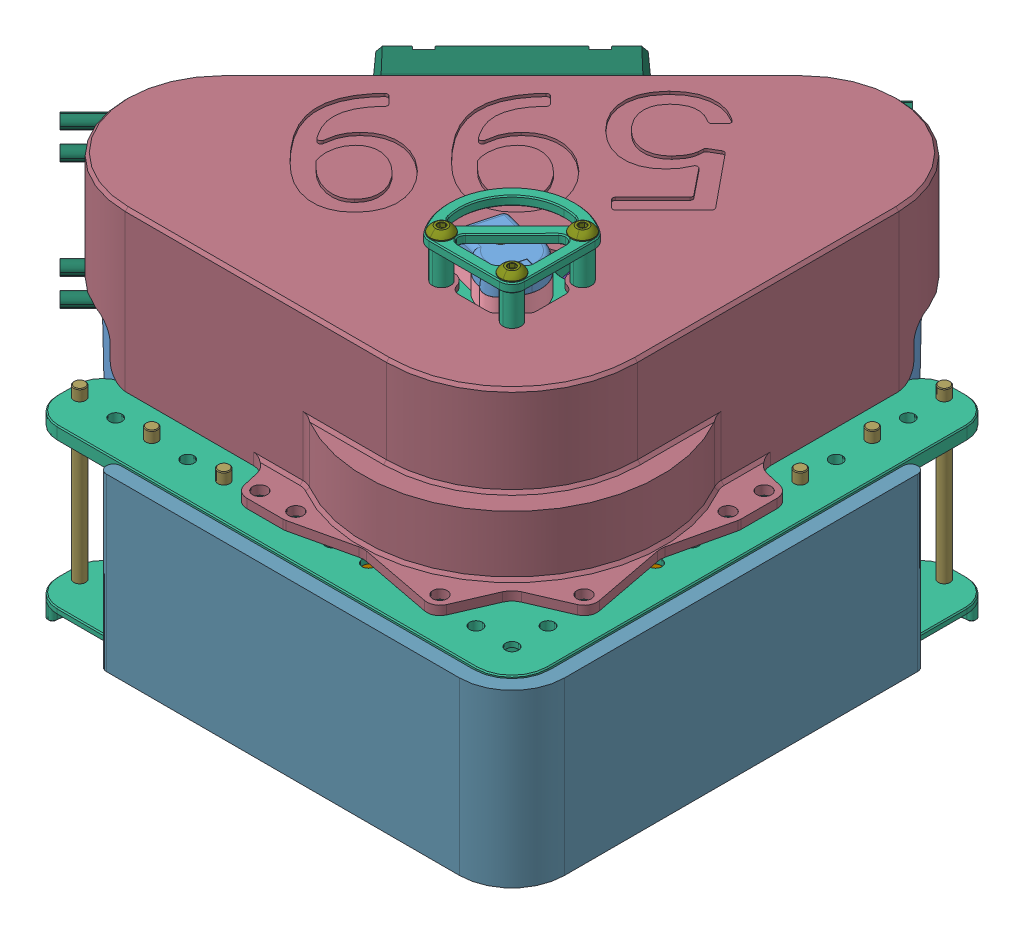
SolidWorks assembly SDS MK4i Swerve Module, NEOs, Deprecated, configuration Default. Lengths in mm.
Overall size (244.9 191.97 235.96).
101 component instances, 51 part files, 24 mates.
Components (placement in the parent):
- SDS MK4i Swerve Module, NEOs(3)^SDS MK4i Swerve Module, NEOs, Deprecated-1: SDS MK4i Swerve Module, NEOs(3)^SDS MK4i Swerve Module, NEOs, Deprecated [Default] at origin size (212.23 191.97 212.38) (virtual)
  - CANcoder Assembly(2)^SDS MK4i Swerve Module, NEOs(3)_SDS MK4i Swerve Module, NEOs, Deprecated-1: CANcoder Assembly(2)^SDS MK4i Swerve Module, NEOs(3)_SDS MK4i Swerve Module, NEOs, Deprecated [Default] at (-66.675 132.3975 -66.675) x (-0.260871 0 0.965374) z (0 1 0) size (21.75 26.91 13.52) (virtual)
    - CANcoder Top Housing(2)^CANcoder Assembly(2)_SDS MK4i Swerve Module, NEOs(3)_SDS MK4i Swerve Module, NEOs, Deprecated-1: CANcoder Top Housing(2)^CANcoder Assembly(2)_SDS MK4i Swerve Module, NEOs(3)_SDS MK4i Swerve Module, NEOs, Deprecated [Default] at origin size (21.53 26.79 8.94) (virtual)
    - CANcoder PCA(2)^CANcoder Assembly(2)_SDS MK4i Swerve Module, NEOs(3)_SDS MK4i Swerve Module, NEOs, Deprecated-1: CANcoder PCA(2)^CANcoder Assembly(2)_SDS MK4i Swerve Module, NEOs(3)_SDS MK4i Swerve Module, NEOs, Deprecated [Default] at (0 0 22.3055) size (15.93 23.27 3.19) (virtual)
    - CANcoder Screw(2)^CANcoder Assembly(2)_SDS MK4i Swerve Module, NEOs(3)_SDS MK4i Swerve Module, NEOs, Deprecated-1: CANcoder Screw(2)^CANcoder Assembly(2)_SDS MK4i Swerve Module, NEOs(3)_SDS MK4i Swerve Module, NEOs, Deprecated [Default] at origin size (4.24 4.24 12.65) (virtual)
    - CANcoder Bottom Housing(2)^CANcoder Assembly(2)_SDS MK4i Swerve Module, NEOs(3)_SDS MK4i Swerve Module, NEOs, Deprecated-1: CANcoder Bottom Housing(2)^CANcoder Assembly(2)_SDS MK4i Swerve Module, NEOs(3)_SDS MK4i Swerve Module, NEOs, Deprecated [Default] at origin size (21.75 26.91 6.35) (virtual)
  - MK4 Billet Wheel Assembly(2)^SDS MK4i Swerve Module, NEOs(3)_SDS MK4i Swerve Module, NEOs, Deprecated-1: MK4 Billet Wheel Assembly(2)^SDS MK4i Swerve Module, NEOs(3)_SDS MK4i Swerve Module, NEOs, Deprecated [Default] at (-66.675 50.7435 -66.675) x (0.707107 0 0.707107) z (0.41117 0.813559 -0.41117) size (42.28 100.13 100.13) (virtual)
    - Wheel, SDS, Nitrile Tread, 4in X 1.5in, Bearing Bore(2)^MK4 Billet Wheel Assembly(2)_SDS MK4i Swerve Module, NEOs(3)_SDS MK4i Swerve Module, NEOs, Deprecated-1: Wheel, SDS, Nitrile Tread, 4in X 1.5in, Bearing Bore(2)^MK4 Billet Wheel Assembly(2)_SDS MK4i Swerve Module, NEOs(3)_SDS MK4i Swerve Module, NEOs, Deprecated [Default] at origin size (42.28 88.9 88.9) (virtual)
    - Tread, Blue Nitrile 4in X 1.5in(2)^MK4 Billet Wheel Assembly(2)_SDS MK4i Swerve Module, NEOs(3)_SDS MK4i Swerve Module, NEOs, Deprecated-1: Tread, Blue Nitrile 4in X 1.5in(2)^MK4 Billet Wheel Assembly(2)_SDS MK4i Swerve Module, NEOs(3)_SDS MK4i Swerve Module, NEOs, Deprecated [Default] at origin size (38.1 100.13 100.13) (virtual)
    - Screw, 10-32 X .75, Button, 91255A269_91255A269(2)^MK4 Billet Wheel Assembly(2)_SDS MK4i Swerve Module, NEOs(3)_SDS MK4i Swerve Module, NEOs, Deprecated-1: Screw, 10-32 X .75, Button, 91255A269_91255A269(2)^MK4 Billet Wheel Assembly(2)_SDS MK4i Swerve Module, NEOs(3)_SDS MK4i Swerve Module, NEOs, Deprecated [Default] at (-4.826 0 20.6375) x (0 -0.847203 -0.531269) z (-1 0 0) size (9.17 9.17 21.62) (virtual)
    - Screw, 10-32 X .75, Button, 91255A269_91255A269(2)^MK4 Billet Wheel Assembly(2)_SDS MK4i Swerve Module, NEOs(3)_SDS MK4i Swerve Module, NEOs, Deprecated-2: Screw, 10-32 X .75, Button, 91255A269_91255A269(2)^MK4 Billet Wheel Assembly(2)_SDS MK4i Swerve Module, NEOs(3)_SDS MK4i Swerve Module, NEOs, Deprecated [Default] at (-4.826 -17.8726 10.3187) x (0 -0.99925 -0.038711) z (-1 0 0) size (9.17 9.17 21.62) (virtual)
    - Screw, 10-32 X .75, Button, 91255A269_91255A269(2)^MK4 Billet Wheel Assembly(2)_SDS MK4i Swerve Module, NEOs(3)_SDS MK4i Swerve Module, NEOs, Deprecated-3: Screw, 10-32 X .75, Button, 91255A269_91255A269(2)^MK4 Billet Wheel Assembly(2)_SDS MK4i Swerve Module, NEOs(3)_SDS MK4i Swerve Module, NEOs, Deprecated [Default] at (-4.826 -17.8726 -10.3187) x (0 -0.986188 -0.165633) z (-1 0 0) size (9.17 9.17 21.62) (virtual)
    - Screw, 10-32 X .75, Button, 91255A269_91255A269(2)^MK4 Billet Wheel Assembly(2)_SDS MK4i Swerve Module, NEOs(3)_SDS MK4i Swerve Module, NEOs, Deprecated-4: Screw, 10-32 X .75, Button, 91255A269_91255A269(2)^MK4 Billet Wheel Assembly(2)_SDS MK4i Swerve Module, NEOs(3)_SDS MK4i Swerve Module, NEOs, Deprecated [Default] at (-4.826 0 -20.6375) x (0 -0.966455 -0.256836) z (-1 0 0) size (9.17 9.17 21.62) (virtual)
    - Screw, 10-32 X .75, Button, 91255A269_91255A269(2)^MK4 Billet Wheel Assembly(2)_SDS MK4i Swerve Module, NEOs(3)_SDS MK4i Swerve Module, NEOs, Deprecated-5: Screw, 10-32 X .75, Button, 91255A269_91255A269(2)^MK4 Billet Wheel Assembly(2)_SDS MK4i Swerve Module, NEOs(3)_SDS MK4i Swerve Module, NEOs, Deprecated [Default] at (-4.826 17.8726 -10.3187) x (0 -0.95104 -0.309068) z (-1 0 0) size (9.17 9.17 21.62) (virtual)
    - Screw, 10-32 X .75, Button, 91255A269_91255A269(2)^MK4 Billet Wheel Assembly(2)_SDS MK4i Swerve Module, NEOs(3)_SDS MK4i Swerve Module, NEOs, Deprecated-6: Screw, 10-32 X .75, Button, 91255A269_91255A269(2)^MK4 Billet Wheel Assembly(2)_SDS MK4i Swerve Module, NEOs(3)_SDS MK4i Swerve Module, NEOs, Deprecated [Default] at (-4.826 17.8726 10.3187) x (0 -0.947988 -0.318305) z (-1 0 0) size (9.17 9.17 21.62) (virtual)
    - Screw, 10-32 X .5, Button, 97763A232_97763A232(2)^MK4 Billet Wheel Assembly(2)_SDS MK4i Swerve Module, NEOs(3)_SDS MK4i Swerve Module, NEOs, Deprecated-1: Screw, 10-32 X .5, Button, 97763A232_97763A232(2)^MK4 Billet Wheel Assembly(2)_SDS MK4i Swerve Module, NEOs(3)_SDS MK4i Swerve Module, NEOs, Deprecated [Default] at (11.1125 -40.6604 7.1695) x (-0.785325 0.107503 0.609678) z (0 -0.984808 0.173648) size (9.17 9.17 15.27) (virtual)
    - Screw, 10-32 X .5, Button, 97763A232_97763A232(2)^MK4 Billet Wheel Assembly(2)_SDS MK4i Swerve Module, NEOs(3)_SDS MK4i Swerve Module, NEOs, Deprecated-2: Screw, 10-32 X .5, Button, 97763A232_97763A232(2)^MK4 Billet Wheel Assembly(2)_SDS MK4i Swerve Module, NEOs(3)_SDS MK4i Swerve Module, NEOs, Deprecated [Default] at (-11.1125 -40.6604 7.1695) x (-0.636812 0.133886 0.759306) z (0 -0.984808 0.173648) size (9.17 9.17 15.27) (virtual)
    - Screw, 10-32 X .5, Button, 97763A232_97763A232(2)^MK4 Billet Wheel Assembly(2)_SDS MK4i Swerve Module, NEOs(3)_SDS MK4i Swerve Module, NEOs, Deprecated-3: Screw, 10-32 X .5, Button, 97763A232_97763A232(2)^MK4 Billet Wheel Assembly(2)_SDS MK4i Swerve Module, NEOs(3)_SDS MK4i Swerve Module, NEOs, Deprecated [Default] at (-11.1125 -40.6604 -7.1695) x (0.726076 -0.119403 0.677168) z (0 -0.984808 -0.173648) size (9.17 9.17 15.27) (virtual)
    - Screw, 10-32 X .5, Button, 97763A232_97763A232(2)^MK4 Billet Wheel Assembly(2)_SDS MK4i Swerve Module, NEOs(3)_SDS MK4i Swerve Module, NEOs, Deprecated-4: Screw, 10-32 X .5, Button, 97763A232_97763A232(2)^MK4 Billet Wheel Assembly(2)_SDS MK4i Swerve Module, NEOs(3)_SDS MK4i Swerve Module, NEOs, Deprecated [Default] at (11.1125 -40.6604 -7.1695) x (0.841108 -0.09392 0.53265) z (0 -0.984808 -0.173648) size (9.17 9.17 15.27) (virtual)
    - Screw, 10-32 X .5, Button, 97763A232_97763A232(2)^MK4 Billet Wheel Assembly(2)_SDS MK4i Swerve Module, NEOs(3)_SDS MK4i Swerve Module, NEOs, Deprecated-5: Screw, 10-32 X .5, Button, 97763A232_97763A232(2)^MK4 Billet Wheel Assembly(2)_SDS MK4i Swerve Module, NEOs(3)_SDS MK4i Swerve Module, NEOs, Deprecated [Default] at (-11.1125 20.6438 -35.7562) x (0.804058 -0.514897 -0.297276) z (0 0.5 -0.866025) size (9.17 9.17 15.27) (virtual)
    - Screw, 10-32 X .5, Button, 97763A232_97763A232(2)^MK4 Billet Wheel Assembly(2)_SDS MK4i Swerve Module, NEOs(3)_SDS MK4i Swerve Module, NEOs, Deprecated-6: Screw, 10-32 X .5, Button, 97763A232_97763A232(2)^MK4 Billet Wheel Assembly(2)_SDS MK4i Swerve Module, NEOs(3)_SDS MK4i Swerve Module, NEOs, Deprecated [Default] at (11.1125 20.6438 -35.7562) x (0.926716 -0.32542 -0.187881) z (0 0.5 -0.866025) size (9.17 9.17 15.27) (virtual)
    - Screw, 10-32 X .5, Button, 97763A232_97763A232(2)^MK4 Billet Wheel Assembly(2)_SDS MK4i Swerve Module, NEOs(3)_SDS MK4i Swerve Module, NEOs, Deprecated-7: Screw, 10-32 X .5, Button, 97763A232_97763A232(2)^MK4 Billet Wheel Assembly(2)_SDS MK4i Swerve Module, NEOs(3)_SDS MK4i Swerve Module, NEOs, Deprecated [Default] at (11.1125 20.6438 35.7562) x (0.200031 0.848523 -0.489895) z (0 0.5 0.866025) size (9.17 9.17 15.27) (virtual)
    - Screw, 10-32 X .5, Button, 97763A232_97763A232(2)^MK4 Billet Wheel Assembly(2)_SDS MK4i Swerve Module, NEOs(3)_SDS MK4i Swerve Module, NEOs, Deprecated-8: Screw, 10-32 X .5, Button, 97763A232_97763A232(2)^MK4 Billet Wheel Assembly(2)_SDS MK4i Swerve Module, NEOs(3)_SDS MK4i Swerve Module, NEOs, Deprecated [Default] at (-11.1125 20.6438 35.7562) x (0.515054 0.74232 -0.428579) z (0 0.5 0.866025) size (9.17 9.17 15.27) (virtual)
  - Screw, 10-32 X .25, Button, 91255A261_91255A261(2)^SDS MK4i Swerve Module, NEOs(3)_SDS MK4i Swerve Module, NEOs, Deprecated-1: Screw, 10-32 X .25, Button, 91255A261_91255A261(2)^SDS MK4i Swerve Module, NEOs(3)_SDS MK4i Swerve Module, NEOs, Deprecated [Default] at (-42.2285 89.5096 -114.6539) x (1 0 0) z (0 -1 0) size (9.17 9.17 8.92) (virtual)
  - Screw, 10-32 X .25, Button, 91255A261_91255A261(2)^SDS MK4i Swerve Module, NEOs(3)_SDS MK4i Swerve Module, NEOs, Deprecated-2: Screw, 10-32 X .25, Button, 91255A261_91255A261(2)^SDS MK4i Swerve Module, NEOs(3)_SDS MK4i Swerve Module, NEOs, Deprecated [Default] at (-104.7513 89.5096 -104.7513) x (0.982082 0 -0.188455) z (0 -1 0) size (9.17 9.17 8.92) (virtual)
  - Screw, 10-32 X .25, Button, 91255A261_91255A261(2)^SDS MK4i Swerve Module, NEOs(3)_SDS MK4i Swerve Module, NEOs, Deprecated-3: Screw, 10-32 X .25, Button, 91255A261_91255A261(2)^SDS MK4i Swerve Module, NEOs(3)_SDS MK4i Swerve Module, NEOs, Deprecated [Default] at (-114.6539 89.5096 -42.2285) x (0.918365 0 -0.395734) z (0 -1 0) size (9.17 9.17 8.92) (virtual)
  - Screw, 10-32 X .25, Button, 91255A261_91255A261(2)^SDS MK4i Swerve Module, NEOs(3)_SDS MK4i Swerve Module, NEOs, Deprecated-4: Screw, 10-32 X .25, Button, 91255A261_91255A261(2)^SDS MK4i Swerve Module, NEOs(3)_SDS MK4i Swerve Module, NEOs, Deprecated [Default] at (-63.5129 89.5096 -12.9199) x (0.8 0 -0.6) z (0 -1 0) size (9.17 9.17 8.92) (virtual)
  - Screw, 10-32 X .25, Button, 91255A261_91255A261(2)^SDS MK4i Swerve Module, NEOs(3)_SDS MK4i Swerve Module, NEOs, Deprecated-5: Screw, 10-32 X .25, Button, 91255A261_91255A261(2)^SDS MK4i Swerve Module, NEOs(3)_SDS MK4i Swerve Module, NEOs, Deprecated [Default] at (-12.9199 89.5096 -63.5129) x (0.63358 0 -0.773678) z (0 -1 0) size (9.17 9.17 8.92) (virtual)
  - Screw, Shoulder, .375 X 2.5, 5_16-18, 91259A634_91259A634(2)^SDS MK4i Swerve Module, NEOs(3)_SDS MK4i Swerve Module, NEOs, Deprecated-1: Screw, Shoulder, .375 X 2.5, 5_16-18, 91259A634_91259A634(2)^SDS MK4i Swerve Module, NEOs(3)_SDS MK4i Swerve Module, NEOs, Deprecated [Default] at (-93.8403 50.7435 -93.8403) x (-0.019195 -0.999631 0.019195) z (0.706846 -0.027146 -0.706846) size (14.29 82.55 14.29) (virtual)
  - Screw, .25-20 X 1 Socket, 91251A542_91251A542(2)^SDS MK4i Swerve Module, NEOs(3)_SDS MK4i Swerve Module, NEOs, Deprecated-1: Screw, .25-20 X 1 Socket, 91251A542_91251A542(2)^SDS MK4i Swerve Module, NEOs(3)_SDS MK4i Swerve Module, NEOs, Deprecated [Default] at (-102.596 101.6 -73.8592) x (0.964329 0 0.264706) z (0 1 0) size (9.53 9.53 31.75) (virtual)
  - Screw, .25-20 X 1 Socket, 91251A542_91251A542(2)^SDS MK4i Swerve Module, NEOs(3)_SDS MK4i Swerve Module, NEOs, Deprecated-2: Screw, .25-20 X 1 Socket, 91251A542_91251A542(2)^SDS MK4i Swerve Module, NEOs(3)_SDS MK4i Swerve Module, NEOs, Deprecated [Default] at (-73.8592 101.6 -102.596) x (0.982082 0 -0.188455) z (0 1 0) size (9.53 9.53 31.75) (virtual)
  - Screw, .25-20 X .625, 91251A539_91251A539(2)^SDS MK4i Swerve Module, NEOs(3)_SDS MK4i Swerve Module, NEOs, Deprecated-1: Screw, .25-20 X .625, 91251A539_91251A539(2)^SDS MK4i Swerve Module, NEOs(3)_SDS MK4i Swerve Module, NEOs, Deprecated [Default] at (-59.4908 83.2802 -30.754) x (1 0 0) z (0 -1 0) size (9.53 9.53 22.23) (virtual)
  - Screw, .25-20 X .625, 91251A539_91251A539(2)^SDS MK4i Swerve Module, NEOs(3)_SDS MK4i Swerve Module, NEOs, Deprecated-2: Screw, .25-20 X .625, 91251A539_91251A539(2)^SDS MK4i Swerve Module, NEOs(3)_SDS MK4i Swerve Module, NEOs, Deprecated [Default] at (-30.754 83.2802 -59.4908) x (0.982082 0 -0.188455) z (0 -1 0) size (9.53 9.53 22.23) (virtual)
  - Screw, .25-20 X .625, 91251A539_91251A539(2)^SDS MK4i Swerve Module, NEOs(3)_SDS MK4i Swerve Module, NEOs, Deprecated-3: Screw, .25-20 X .625, 91251A539_91251A539(2)^SDS MK4i Swerve Module, NEOs(3)_SDS MK4i Swerve Module, NEOs, Deprecated [Default] at (-66.675 126.2062 -66.675) x (0 0 1) z (0 1 0) size (9.53 9.53 22.23) (virtual)
  - Screw, 12-24 X .625, Flat, 91253A282_91253A282(2)^SDS MK4i Swerve Module, NEOs(3)_SDS MK4i Swerve Module, NEOs, Deprecated-1: Screw, 12-24 X .625, Flat, 91253A282_91253A282(2)^SDS MK4i Swerve Module, NEOs(3)_SDS MK4i Swerve Module, NEOs, Deprecated [Default] at (-46.8646 122.8979 -46.8646) x (-0.837169 0 -0.546944) z (0 1 0) size (10.72 10.72 15.88) (virtual)
  - Screw, 10-32 X 1.375, 90044A202_90044A202(2)^SDS MK4i Swerve Module, NEOs(3)_SDS MK4i Swerve Module, NEOs, Deprecated-1: Screw, 10-32 X 1.375, 90044A202_90044A202(2)^SDS MK4i Swerve Module, NEOs(3)_SDS MK4i Swerve Module, NEOs, Deprecated [Default] at (-34.518 138.8491 -146.05) x (-0.434408 0 0.900716) z (0 1 0) size (7.94 7.94 39.75) (virtual)
  - Screw, 10-32 X 1.375, 90044A202_90044A202(2)^SDS MK4i Swerve Module, NEOs(3)_SDS MK4i Swerve Module, NEOs, Deprecated-2: Screw, 10-32 X 1.375, 90044A202_90044A202(2)^SDS MK4i Swerve Module, NEOs(3)_SDS MK4i Swerve Module, NEOs, Deprecated [Default] at (-78.512 138.8491 -171.45) x (0.192903 0 0.981218) z (0 1 0) size (7.94 7.94 39.75) (virtual)
  - Screw, 10-32 X 1.375, 90044A202_90044A202(2)^SDS MK4i Swerve Module, NEOs(3)_SDS MK4i Swerve Module, NEOs, Deprecated-3: Screw, 10-32 X 1.375, 90044A202_90044A202(2)^SDS MK4i Swerve Module, NEOs(3)_SDS MK4i Swerve Module, NEOs, Deprecated [Default] at (-171.45 138.8491 -78.512) x (0.421632 0 0.906767) z (0 1 0) size (7.94 7.94 39.75) (virtual)
  - Screw, 10-32 X 1.375, 90044A202_90044A202(2)^SDS MK4i Swerve Module, NEOs(3)_SDS MK4i Swerve Module, NEOs, Deprecated-4: Screw, 10-32 X 1.375, 90044A202_90044A202(2)^SDS MK4i Swerve Module, NEOs(3)_SDS MK4i Swerve Module, NEOs, Deprecated [Default] at (-146.05 138.8491 -34.518) x (0.201272 0 -0.979535) z (0 1 0) size (7.94 7.94 39.75) (virtual)
  - Screw, 10-32 X 1.375, 90044A202_90044A202(2)^SDS MK4i Swerve Module, NEOs(3)_SDS MK4i Swerve Module, NEOs, Deprecated-5: Screw, 10-32 X 1.375, 90044A202_90044A202(2)^SDS MK4i Swerve Module, NEOs(3)_SDS MK4i Swerve Module, NEOs, Deprecated [Default] at (-43.815 138.8491 -180.747) x (-0.25688 0 0.966443) z (0 1 0) size (7.94 7.94 39.75) (virtual)
  - Screw, 10-32 X 1.375, 90044A202_90044A202(2)^SDS MK4i Swerve Module, NEOs(3)_SDS MK4i Swerve Module, NEOs, Deprecated-6: Screw, 10-32 X 1.375, 90044A202_90044A202(2)^SDS MK4i Swerve Module, NEOs(3)_SDS MK4i Swerve Module, NEOs, Deprecated [Default] at (-180.747 138.8491 -43.815) x (-0.042501 0 0.999096) z (0 1 0) size (7.94 7.94 39.75) (virtual)
  - Screw, 10-32 X 2.25, 91251A354_91251A354(2)^SDS MK4i Swerve Module, NEOs(3)_SDS MK4i Swerve Module, NEOs, Deprecated-1: Screw, 10-32 X 2.25, 91251A354_91251A354(2)^SDS MK4i Swerve Module, NEOs(3)_SDS MK4i Swerve Module, NEOs, Deprecated [Default] at (-124.5154 92.0115 -124.5154) x (-0.750514 0 0.660855) z (0 -1 0) size (7.92 7.92 61.98) (virtual)
  - Screw, 10-32 X 2.25, 91251A354_91251A354(2)^SDS MK4i Swerve Module, NEOs(3)_SDS MK4i Swerve Module, NEOs, Deprecated-2: Screw, 10-32 X 2.25, 91251A354_91251A354(2)^SDS MK4i Swerve Module, NEOs(3)_SDS MK4i Swerve Module, NEOs, Deprecated [Default] at (-32.639 92.0115 -114.3) x (-0.612525 0 0.790452) z (0 -1 0) size (7.92 7.92 61.98) (virtual)
  - Screw, 10-32 X 2.25, 91251A354_91251A354(2)^SDS MK4i Swerve Module, NEOs(3)_SDS MK4i Swerve Module, NEOs, Deprecated-3: Screw, 10-32 X 2.25, 91251A354_91251A354(2)^SDS MK4i Swerve Module, NEOs(3)_SDS MK4i Swerve Module, NEOs, Deprecated [Default] at (-114.3 92.0115 -32.639) x (-0.427723 0 0.90391) z (0 -1 0) size (7.92 7.92 61.98) (virtual)
  - Screw, 10-32 X 2.25, 91251A354_91251A354(2)^SDS MK4i Swerve Module, NEOs(3)_SDS MK4i Swerve Module, NEOs, Deprecated-4: Screw, 10-32 X 2.25, 91251A354_91251A354(2)^SDS MK4i Swerve Module, NEOs(3)_SDS MK4i Swerve Module, NEOs, Deprecated [Default] at (-12.7 98.4885 -12.7) x (0.90391 0 -0.427723) z (0 1 0) size (7.92 7.92 61.98) (virtual)
  - Screw, 8-32 X .875, Button, 91255A166_91255A166(2)^SDS MK4i Swerve Module, NEOs(3)_SDS MK4i Swerve Module, NEOs, Deprecated-1: Screw, 8-32 X .875, Button, 91255A166_91255A166(2)^SDS MK4i Swerve Module, NEOs(3)_SDS MK4i Swerve Module, NEOs, Deprecated [Default] at (-80.9791 172.8661 -56.1146) x (1 0 0) z (0 1 0) size (7.92 7.92 24.45) (virtual)
  - Screw, 8-32 X .875, Button, 91255A166_91255A166(2)^SDS MK4i Swerve Module, NEOs(3)_SDS MK4i Swerve Module, NEOs, Deprecated-2: Screw, 8-32 X .875, Button, 91255A166_91255A166(2)^SDS MK4i Swerve Module, NEOs(3)_SDS MK4i Swerve Module, NEOs, Deprecated [Default] at (-56.1231 172.8661 -56.1146) x (0.982082 0 -0.188455) z (0 1 0) size (7.92 7.92 24.45) (virtual)
  - Screw, 8-32 X .875, Button, 91255A166_91255A166(2)^SDS MK4i Swerve Module, NEOs(3)_SDS MK4i Swerve Module, NEOs, Deprecated-3: Screw, 8-32 X .875, Button, 91255A166_91255A166(2)^SDS MK4i Swerve Module, NEOs(3)_SDS MK4i Swerve Module, NEOs, Deprecated [Default] at (-56.1231 172.8661 -80.9854) x (0.918365 0 -0.395734) z (0 1 0) size (7.92 7.92 24.45) (virtual)
  - Shim, 8mm ID X 14mm OD X .5mm Thick, 98055A115_98055A115(2)^SDS MK4i Swerve Module, NEOs(3)_SDS MK4i Swerve Module, NEOs, Deprecated-1: Shim, 8mm ID X 14mm OD X .5mm Thick, 98055A115_98055A115(2)^SDS MK4i Swerve Module, NEOs(3)_SDS MK4i Swerve Module, NEOs, Deprecated [Default] at (-46.8646 73.9775 -46.8646) x (0.942304 0 -0.334759) z (0.334759 0 0.942304) size (14 1 14) (virtual)
  - Bearing, 6802(2)^SDS MK4i Swerve Module, NEOs(3)_SDS MK4i Swerve Module, NEOs, Deprecated-1: Bearing, 6802(2)^SDS MK4i Swerve Module, NEOs(3)_SDS MK4i Swerve Module, NEOs, Deprecated [Default] at (-66.675 138.5216 -66.675) x (0.972423 0 0.233226) z (-0.233226 0 0.972423) size (24 5 24) (virtual)
  - Bearing, 6802(2)^SDS MK4i Swerve Module, NEOs(3)_SDS MK4i Swerve Module, NEOs, Deprecated-2: Bearing, 6802(2)^SDS MK4i Swerve Module, NEOs(3)_SDS MK4i Swerve Module, NEOs, Deprecated [Default] at (-66.675 147.8675 -66.675) x (0.877163 0 0.480193) z (-0.480193 0 0.877163) size (24 5 24) (virtual)
  - Bearing, 6802(2)^SDS MK4i Swerve Module, NEOs(3)_SDS MK4i Swerve Module, NEOs, Deprecated-3: Bearing, 6802(2)^SDS MK4i Swerve Module, NEOs(3)_SDS MK4i Swerve Module, NEOs, Deprecated [Default] at (-66.675 118.1216 -66.675) x (0.639486 0 0.768802) z (-0.768802 0 0.639486) size (24 5 24) (virtual)
  - Bearing, R6ZZ(2)^SDS MK4i Swerve Module, NEOs(3)_SDS MK4i Swerve Module, NEOs, Deprecated-1: Bearing, R6ZZ(2)^SDS MK4i Swerve Module, NEOs(3)_SDS MK4i Swerve Module, NEOs, Deprecated [Default] at (-79.2721 50.7435 -79.2721) x (-0.694824 0.18558 0.694824) z (0.131225 0.982629 -0.131225) size (22.23 7.14 22.23) (virtual)
  - Bearing, R8ZZ(2)^SDS MK4i Swerve Module, NEOs(3)_SDS MK4i Swerve Module, NEOs, Deprecated-1: Bearing, R8ZZ(2)^SDS MK4i Swerve Module, NEOs(3)_SDS MK4i Swerve Module, NEOs, Deprecated [Default] at (-57.5286 50.7435 -57.5286) x (-0.158587 -0.974526 0.158587) z (-0.689094 0.224275 0.689094) size (32.17 11.7 36.1) (virtual)
  - Bearing, 688(2)^SDS MK4i Swerve Module, NEOs(3)_SDS MK4i Swerve Module, NEOs, Deprecated-1: Bearing, 688(2)^SDS MK4i Swerve Module, NEOs(3)_SDS MK4i Swerve Module, NEOs, Deprecated [Default] at (-46.8646 71.4775 -46.8646) x (0 -1 0) z (-0.336154 0 0.941807) size (5 16 16) (virtual)
  - Bearing, .375 ThunderHex, Flanged, 217-5829(2)^SDS MK4i Swerve Module, NEOs(3)_SDS MK4i Swerve Module, NEOs, Deprecated-1: Bearing, .375 ThunderHex, Flanged, 217-5829(2)^SDS MK4i Swerve Module, NEOs(3)_SDS MK4i Swerve Module, NEOs, Deprecated [Default] at (-46.8646 102.3938 -46.8646) x (0.903016 0 0.429606) z (-0.429606 0 0.903016) size (24.51 7.14 24.51) (virtual)
  - Bevel Gear, 1545(2)^SDS MK4i Swerve Module, NEOs(3)_SDS MK4i Swerve Module, NEOs, Deprecated-1: Bevel Gear, 1545(2)^SDS MK4i Swerve Module, NEOs(3)_SDS MK4i Swerve Module, NEOs, Deprecated [Default] at (-46.8646 84.4935 -46.8646) x (-0.830686 0 -0.556741) z (-0.556741 0 0.830686) size (25.31 14.25 25.48) (virtual)
  - Bearing, 688(2)^SDS MK4i Swerve Module, NEOs(3)_SDS MK4i Swerve Module, NEOs, Deprecated-2: Bearing, 688(2)^SDS MK4i Swerve Module, NEOs(3)_SDS MK4i Swerve Module, NEOs, Deprecated [Default] at (-128.0498 97.5125 -83.2602) x (0 -1 0) z (-0.444562 0 0.895748) size (5 16 16) (virtual)
  - Bearing, R188ZZ, 217-3489(2)^SDS MK4i Swerve Module, NEOs(3)_SDS MK4i Swerve Module, NEOs, Deprecated-1: Bearing, R188ZZ, 217-3489(2)^SDS MK4i Swerve Module, NEOs(3)_SDS MK4i Swerve Module, NEOs, Deprecated [Default] at (-77.6314 97.6313 -123.9376) x (-0.188457 0 -0.982081) z (0.982081 0 -0.188457) size (12.7 4.76 12.7) (virtual)
  - Bearing, 688(2)^SDS MK4i Swerve Module, NEOs(3)_SDS MK4i Swerve Module, NEOs, Deprecated-3: Bearing, 688(2)^SDS MK4i Swerve Module, NEOs(3)_SDS MK4i Swerve Module, NEOs, Deprecated [Default] at (-77.6314 150.1375 -123.9376) x (0 -1 0) z (-0.336154 0 0.941807) size (5 16 16) (virtual)
  - Bearing, 688(2)^SDS MK4i Swerve Module, NEOs(3)_SDS MK4i Swerve Module, NEOs, Deprecated-4: Bearing, 688(2)^SDS MK4i Swerve Module, NEOs(3)_SDS MK4i Swerve Module, NEOs, Deprecated [Default] at (-128.0498 148.8167 -83.2602) x (0 -1 0) z (-0.336154 0 0.941807) size (5 16 16) (virtual)
  - Bearing, A035XPO_SA035XPO(2)^SDS MK4i Swerve Module, NEOs(3)_SDS MK4i Swerve Module, NEOs, Deprecated-1: Bearing, A035XPO_SA035XPO(2)^SDS MK4i Swerve Module, NEOs(3)_SDS MK4i Swerve Module, NEOs, Deprecated [Default] at (-66.675 95.25 -66.675) x (0.978935 0 0.20417) z (-0.20417 0 0.978935) size (101.6 6.35 101.6) (virtual)
  - Double Gear, 20DP, 28T, 50T(2)^SDS MK4i Swerve Module, NEOs(3)_SDS MK4i Swerve Module, NEOs, Deprecated-1: Double Gear, 20DP, 28T, 50T(2)^SDS MK4i Swerve Module, NEOs(3)_SDS MK4i Swerve Module, NEOs, Deprecated [Default] at (-66.675 110.1225 -66.675) x (-0.730582 0 -0.682825) z (0 1 0) size (65.97 66.04 34.49) (virtual)
  - Gear, 50T, 20DP, .375Hex(2)^SDS MK4i Swerve Module, NEOs(3)_SDS MK4i Swerve Module, NEOs, Deprecated-1: Gear, 50T, 20DP, .375Hex(2)^SDS MK4i Swerve Module, NEOs(3)_SDS MK4i Swerve Module, NEOs, Deprecated [Default] at (-128.0498 139.8651 -83.2602) x (0.985885 0 -0.167422) z (0 1 0) size (65.97 66.04 12.65) (virtual)
  - Gear, 50T, 20DP, .375Hex(2)^SDS MK4i Swerve Module, NEOs(3)_SDS MK4i Swerve Module, NEOs, Deprecated-2: Gear, 50T, 20DP, .375Hex(2)^SDS MK4i Swerve Module, NEOs(3)_SDS MK4i Swerve Module, NEOs, Deprecated [Default] at (-77.6314 128.4859 -123.9376) x (-0.963721 0 0.266911) z (0 1 0) size (65.97 66.04 12.65) (virtual)
  - Bevel Gear, 4515(2)^SDS MK4i Swerve Module, NEOs(3)_SDS MK4i Swerve Module, NEOs, Deprecated-1: Bevel Gear, 4515(2)^SDS MK4i Swerve Module, NEOs(3)_SDS MK4i Swerve Module, NEOs, Deprecated [Default] at (-54.7746 50.7435 -54.7746) x (0.575273 -0.581482 -0.575273) z (-0.41117 -0.813559 0.41117) size (68.38 7.77 68.42) (virtual)
  - Gear, 20DP, 16T, .375Hex, 217-5451(2)^SDS MK4i Swerve Module, NEOs(3)_SDS MK4i Swerve Module, NEOs, Deprecated-1: Gear, 20DP, 16T, .375Hex, 217-5451(2)^SDS MK4i Swerve Module, NEOs(3)_SDS MK4i Swerve Module, NEOs, Deprecated [Default] at (-46.8646 115.8375 -46.8646) x (0.993265 0 0.115868) z (0 -1 0) size (22.6 22.6 12.6) (virtual)
  - MK4i Steering Shaft Tall(2)^SDS MK4i Swerve Module, NEOs(3)_SDS MK4i Swerve Module, NEOs, Deprecated-1: MK4i Steering Shaft Tall(2)^SDS MK4i Swerve Module, NEOs(3)_SDS MK4i Swerve Module, NEOs, Deprecated [Default] at (-77.6314 152.5105 -123.9376) x (0.998641 0 -0.05212) z (0.05212 0 0.998641) size (17.78 57.04 17.78) (virtual)
  - MK4i Steering Shaft Spacer(2)^SDS MK4i Swerve Module, NEOs(3)_SDS MK4i Swerve Module, NEOs, Deprecated-1: MK4i Steering Shaft Spacer(2)^SDS MK4i Swerve Module, NEOs(3)_SDS MK4i Swerve Module, NEOs, Deprecated [Default] at (-77.6314 134.8105 -123.9376) x (-0.728275 0 -0.685285) z (0.685285 0 -0.728275) size (13.36 12.7 13.36) (virtual)
  - MK4 Intermediate Shaft(2)^SDS MK4i Swerve Module, NEOs(3)_SDS MK4i Swerve Module, NEOs, Deprecated-1: MK4 Intermediate Shaft(2)^SDS MK4i Swerve Module, NEOs(3)_SDS MK4i Swerve Module, NEOs, Deprecated [Default] at (-46.8646 68.3577 -46.8646) x (0.999953 0 0.009669) z (-0.009669 0 0.999953) size (11.68 51.44 11.68) (virtual)
  - MK3 Center Column(2)^SDS MK4i Swerve Module, NEOs(3)_SDS MK4i Swerve Module, NEOs, Deprecated-1: MK3 Center Column(2)^SDS MK4i Swerve Module, NEOs(3)_SDS MK4i Swerve Module, NEOs, Deprecated [Default] at (-66.675 113.0816 -66.675) x (-0.707107 0 0.707107) z (-0.707107 0 -0.707107) size (17.27 40.32 17.27) (virtual)
  - MK4i Shaft, Drive Idler(2)^SDS MK4i Swerve Module, NEOs(3)_SDS MK4i Swerve Module, NEOs, Deprecated-1: MK4i Shaft, Drive Idler(2)^SDS MK4i Swerve Module, NEOs(3)_SDS MK4i Swerve Module, NEOs, Deprecated [Default] at (-128.0498 100.0125 -83.2602) size (13.36 56.18 13.36) (virtual)
  - Screw, 3-48 X .1875, Pan Phillips, 90272A091_90272A091(2)^SDS MK4i Swerve Module, NEOs(3)_SDS MK4i Swerve Module, NEOs, Deprecated-1: Screw, 3-48 X .1875, Pan Phillips, 90272A091_90272A091(2)^SDS MK4i Swerve Module, NEOs(3)_SDS MK4i Swerve Module, NEOs, Deprecated [Default] at (-68.5859 150.495 -73.8677) x (1 0 0) z (0 1 0) size (4.9 4.9 6.49) (virtual)
  - Screw, 3-48 X .1875, Pan Phillips, 90272A091_90272A091(2)^SDS MK4i Swerve Module, NEOs(3)_SDS MK4i Swerve Module, NEOs, Deprecated-2: Screw, 3-48 X .1875, Pan Phillips, 90272A091_90272A091(2)^SDS MK4i Swerve Module, NEOs(3)_SDS MK4i Swerve Module, NEOs, Deprecated [Default] at (-64.7641 150.495 -59.4823) x (0.911631 0 -0.411009) z (0 1 0) size (4.9 4.9 6.49) (virtual)
  - magnet(2)^SDS MK4i Swerve Module, NEOs(3)_SDS MK4i Swerve Module, NEOs, Deprecated-1: magnet(2)^SDS MK4i Swerve Module, NEOs(3)_SDS MK4i Swerve Module, NEOs, Deprecated [Default] at (-66.675 140.7033 -66.675) x (-0.536649 0 -0.843806) z (0.843806 0 -0.536649) size (6.35 12.7 6.35) (virtual)
  - Motor, NEO(2)^SDS MK4i Swerve Module, NEOs(3)_SDS MK4i Swerve Module, NEOs, Deprecated-1: Motor, NEO(2)^SDS MK4i Swerve Module, NEOs(3)_SDS MK4i Swerve Module, NEOs, Deprecated [Default] at (-158.75 119.0625 -56.515) x (0.866025 0 -0.5) z (0 1 0) size (59.98 59.98 90) (virtual)
  - Motor, NEO(2)^SDS MK4i Swerve Module, NEOs(3)_SDS MK4i Swerve Module, NEOs, Deprecated-2: Motor, NEO(2)^SDS MK4i Swerve Module, NEOs(3)_SDS MK4i Swerve Module, NEOs, Deprecated [Default] at (-56.515 119.0625 -158.75) x (0.866025 0 0.5) z (0 1 0) size (59.98 59.98 90) (virtual)
  - Shim, 8mm ID X 14mm OD X .5mm Thick, 98055A115_98055A115(2)^SDS MK4i Swerve Module, NEOs(3)_SDS MK4i Swerve Module, NEOs, Deprecated-2: Shim, 8mm ID X 14mm OD X .5mm Thick, 98055A115_98055A115(2)^SDS MK4i Swerve Module, NEOs(3)_SDS MK4i Swerve Module, NEOs, Deprecated [Default] at (-56.515 122.5625 -158.75) x (0.942304 0 -0.334759) z (0.334759 0 0.942304) size (14 1 14) (virtual)
  - Gear, 20DP, 14T, 8mm REV1(2)^SDS MK4i Swerve Module, NEOs(3)_SDS MK4i Swerve Module, NEOs, Deprecated-1: Gear, 20DP, 14T, 8mm REV1(2)^SDS MK4i Swerve Module, NEOs(3)_SDS MK4i Swerve Module, NEOs, Deprecated [Default] at (-56.515 123.5625 -158.75) x (0 1 0) z (-0.866025 0 -0.5) size (12.7 19.97 20.32) (virtual)
  - Retaining Ring, 8mm, 98430A132_98430A132(2)^SDS MK4i Swerve Module, NEOs(3)_SDS MK4i Swerve Module, NEOs, Deprecated-1: Retaining Ring, 8mm, 98430A132_98430A132(2)^SDS MK4i Swerve Module, NEOs(3)_SDS MK4i Swerve Module, NEOs, Deprecated [Default] at (-56.515 136.2625 -158.75) x (0 1 0) z (-0.12503 0 0.992153) size (1.07 14.83 14.83) (virtual)
  - Gear, 20DP, 14T, 8mm REV1(2)^SDS MK4i Swerve Module, NEOs(3)_SDS MK4i Swerve Module, NEOs, Deprecated-2: Gear, 20DP, 14T, 8mm REV1(2)^SDS MK4i Swerve Module, NEOs(3)_SDS MK4i Swerve Module, NEOs, Deprecated [Default] at (-158.75 133.675 -56.515) x (0 1 0) z (-0.866025 0 0.5) size (12.7 19.97 20.32) (virtual)
  - Spacer, 8mmID X .437 OD X 0.437 L(2)^SDS MK4i Swerve Module, NEOs(3)_SDS MK4i Swerve Module, NEOs, Deprecated-1: Spacer, 8mmID X .437 OD X 0.437 L(2)^SDS MK4i Swerve Module, NEOs(3)_SDS MK4i Swerve Module, NEOs, Deprecated [Default] at (-158.75 122.5625 -56.515) size (11.11 11.11 11.11) (virtual)
  - Retaining Ring, 8mm, 98430A132_98430A132(2)^SDS MK4i Swerve Module, NEOs(3)_SDS MK4i Swerve Module, NEOs, Deprecated-2: Retaining Ring, 8mm, 98430A132_98430A132(2)^SDS MK4i Swerve Module, NEOs(3)_SDS MK4i Swerve Module, NEOs, Deprecated [Default] at (-158.75 146.375 -56.515) x (0 1 0) z (0.064186 0 0.997938) size (1.07 14.83 14.83) (virtual)
  - Machine Key, 2 X 2 X 12mm(2)^SDS MK4i Swerve Module, NEOs(3)_SDS MK4i Swerve Module, NEOs, Deprecated-1: Machine Key, 2 X 2 X 12mm(2)^SDS MK4i Swerve Module, NEOs(3)_SDS MK4i Swerve Module, NEOs, Deprecated [Default] at (-160.675 140.025 -59.8492) x (-0.866025 0 0.5) z (-0.5 0 -0.866025) size (2 12 2) (virtual)
  - Machine Key, 2 X 2 X 12mm(2)^SDS MK4i Swerve Module, NEOs(3)_SDS MK4i Swerve Module, NEOs, Deprecated-2: Machine Key, 2 X 2 X 12mm(2)^SDS MK4i Swerve Module, NEOs(3)_SDS MK4i Swerve Module, NEOs, Deprecated [Default] at (-54.59 129.9125 -162.0842) x (0.866025 0 0.5) z (-0.5 0 0.866025) size (2 12 2) (virtual)
  - MK4i Master Part_NEO Config(2)^SDS MK4i Swerve Module, NEOs(3)_SDS MK4i Swerve Module, NEOs, Deprecated-1: MK4i Master Part_NEO Config(2)^SDS MK4i Swerve Module, NEOs(3)_SDS MK4i Swerve Module, NEOs, Deprecated [Default] at origin size (189.87 134.14 189.87) (virtual)
  - MK3 Base Pulley Tall(2)^SDS MK4i Swerve Module, NEOs(3)_SDS MK4i Swerve Module, NEOs, Deprecated-1: MK3 Base Pulley Tall(2)^SDS MK4i Swerve Module, NEOs(3)_SDS MK4i Swerve Module, NEOs, Deprecated [Default] at (-66.675 98.425 -66.675) x (-0.707107 0 0.707107) z (-0.707107 0 -0.707107) size (98.42 27.08 98.42) (virtual)
  - Belt, 320-5M-15(2)^SDS MK4i Swerve Module, NEOs(3)_SDS MK4i Swerve Module, NEOs, Deprecated-1: Belt, 320-5M-15(2)^SDS MK4i Swerve Module, NEOs(3)_SDS MK4i Swerve Module, NEOs, Deprecated [Default] at (-66.675 109.752 -66.675) x (0.982183 0 -0.187927) z (0.187927 0 0.982183) size (97.78 15 116.29) (virtual)
  - Wheel Mount A(2)^SDS MK4i Swerve Module, NEOs(3)_SDS MK4i Swerve Module, NEOs, Deprecated-1: Wheel Mount A(2)^SDS MK4i Swerve Module, NEOs(3)_SDS MK4i Swerve Module, NEOs, Deprecated [Default] at (-88.2276 50.7435 -88.2276) x (-0.707107 0 -0.707107) z (0.707107 0 -0.707107) size (17.09 49.74 57.15) (virtual)
  - Wheel Mount B Gen2(2)^SDS MK4i Swerve Module, NEOs(3)_SDS MK4i Swerve Module, NEOs, Deprecated-1: Wheel Mount B Gen2(2)^SDS MK4i Swerve Module, NEOs(3)_SDS MK4i Swerve Module, NEOs, Deprecated [Default] at (-45.1224 50.7435 -45.1224) x (-0.707107 0 -0.707107) z (0.707107 0 -0.707107) size (15.88 49.27 57.15) (virtual)
  - MK4 Wheel Spacer(2)^SDS MK4i Swerve Module, NEOs(3)_SDS MK4i Swerve Module, NEOs, Deprecated-1: MK4 Wheel Spacer(2)^SDS MK4i Swerve Module, NEOs(3)_SDS MK4i Swerve Module, NEOs, Deprecated [Default] at (-76.7015 50.7435 -76.7015) x (-0.707107 0 -0.707107) z (0.522819 -0.67329 -0.522819) size (36.72 15.11 15.11) (virtual)
- Copy of Configurable SHCS^SDS MK4i Swerve Module, NEOs, Deprecated-1: Copy of Configurable SHCS^SDS MK4i Swerve Module, NEOs, Deprecated [8-32 x 2.5] at (-12.7 36.2839 -114.3) x (0 1 0) z (0 0 1) size (67.87 6.86 6.86) (virtual)
- Copy of Configurable SHCS^SDS MK4i Swerve Module, NEOs, Deprecated-2: Copy of Configurable SHCS^SDS MK4i Swerve Module, NEOs, Deprecated [8-32 x 2.5] at (-12.7 36.2839 -139.7) x (0 1 0) z (0 0 1) size (67.87 6.86 6.86) (virtual)
- Copy of Configurable SHCS^SDS MK4i Swerve Module, NEOs, Deprecated-3: Copy of Configurable SHCS^SDS MK4i Swerve Module, NEOs, Deprecated [8-32 x 2.5] at (-12.7 36.2839 -165.1) x (0 1 0) z (0 0 1) size (67.87 6.86 6.86) (virtual)
- Copy of Configurable SHCS^SDS MK4i Swerve Module, NEOs, Deprecated-4: Copy of Configurable SHCS^SDS MK4i Swerve Module, NEOs, Deprecated [8-32 x 2.5] at (-165.1 36.2839 -12.7) x (0 1 0) z (0 0 1) size (67.87 6.86 6.86) (virtual)
- Copy of Configurable SHCS^SDS MK4i Swerve Module, NEOs, Deprecated-6: Copy of Configurable SHCS^SDS MK4i Swerve Module, NEOs, Deprecated [8-32 x 2.5] at (-139.7 36.2839 -12.7) x (0 1 0) z (0 0 1) size (67.87 6.86 6.86) (virtual)
- Copy of Configurable SHCS^SDS MK4i Swerve Module, NEOs, Deprecated-7: Copy of Configurable SHCS^SDS MK4i Swerve Module, NEOs, Deprecated [8-32 x 2.5] at (-114.3 36.2839 -12.7) x (0 1 0) z (0 0 1) size (67.87 6.86 6.86) (virtual)
- mk4i full cover with spark mounts-1: mk4i full cover with spark mounts [Default] at (-25.4 155.9875 -25.4) x (0 0 1) z (1 0 0) size (184.75 97.25 184.75)
- mk4i bumper legalizer-1: mk4i bumper legalizer [Default] at (-12.7 44.45 -12.7) size (145.54 60.32 145.54)
- Spark Max REV-11-2158-1: Spark Max REV-11-2158 [Default] at (-147.9835 86.4575 -147.9835) x (0.707107 0 -0.707107) z (0 -1 0) size (212.48 29.65 34.5)
- Spark Max REV-11-2158-2: Spark Max REV-11-2158 [Default] at (-147.9835 131.1175 -147.9835) x (0.707107 0 -0.707107) z (0 -1 0) size (212.48 29.65 34.5)
Mates (geometry in assembly coordinates):
- Concentric11: concentric aligned: cylinder of SDS MK4i Swerve Module, NEOs(3)^SDS MK4i Swerve Module, NEOs, Deprecated-1/MK4i Master Part_NEO Config(2)^SDS MK4i Swerve Module, NEOs(3)_SDS MK4i Swerve Module, NEOs, Deprecated-1 through (-12.7 36.5125 -114.3) axis (0 1 0) radius 2.0828; cylinder of Copy of Configurable SHCS^SDS MK4i Swerve Module, NEOs, Deprecated-1 through (-12.7 103.9495 -114.3) axis (0 1 0) radius 3.429
- Coincident11: coincident anti-aligned: plane of SDS MK4i Swerve Module, NEOs(3)^SDS MK4i Swerve Module, NEOs, Deprecated-1/MK4i Master Part_NEO Config(2)^SDS MK4i Swerve Module, NEOs(3)_SDS MK4i Swerve Module, NEOs, Deprecated-1 through (-12.7 40.4495 -114.3) normal (0 -1 0); plane of Copy of Configurable SHCS^SDS MK4i Swerve Module, NEOs, Deprecated-1 through (-12.7 40.4495 -117.729) normal (0 1 0)
- Concentric21: concentric aligned: cylinder of SDS MK4i Swerve Module, NEOs(3)^SDS MK4i Swerve Module, NEOs, Deprecated-1/MK4i Master Part_NEO Config(2)^SDS MK4i Swerve Module, NEOs(3)_SDS MK4i Swerve Module, NEOs, Deprecated-1 through (-12.7 36.5125 -139.7) axis (0 1 0) radius 2.0828; cylinder of Copy of Configurable SHCS^SDS MK4i Swerve Module, NEOs, Deprecated-2 through (-12.7 103.9495 -139.7) axis (0 1 0) radius 3.429
- Coincident21: coincident anti-aligned: plane of SDS MK4i Swerve Module, NEOs(3)^SDS MK4i Swerve Module, NEOs, Deprecated-1/MK4i Master Part_NEO Config(2)^SDS MK4i Swerve Module, NEOs(3)_SDS MK4i Swerve Module, NEOs, Deprecated-1 through (-12.7 40.4495 -139.7) normal (0 -1 0); plane of Copy of Configurable SHCS^SDS MK4i Swerve Module, NEOs, Deprecated-2 through (-12.7 40.4495 -143.129) normal (0 1 0)
- Concentric31: concentric anti-aligned: cylinder of SDS MK4i Swerve Module, NEOs(3)^SDS MK4i Swerve Module, NEOs, Deprecated-1/MK4i Master Part_NEO Config(2)^SDS MK4i Swerve Module, NEOs(3)_SDS MK4i Swerve Module, NEOs, Deprecated-1 through (-12.7 40.4495 -165.1) axis (0 -1 0) radius 3.5242; cylinder of Copy of Configurable SHCS^SDS MK4i Swerve Module, NEOs, Deprecated-3 through (-12.7 103.9495 -165.1) axis (0 1 0) radius 3.429
- Coincident31: coincident anti-aligned: plane of SDS MK4i Swerve Module, NEOs(3)^SDS MK4i Swerve Module, NEOs, Deprecated-1/MK4i Master Part_NEO Config(2)^SDS MK4i Swerve Module, NEOs(3)_SDS MK4i Swerve Module, NEOs, Deprecated-1 through (-12.7 40.4495 -165.1) normal (0 -1 0); plane of Copy of Configurable SHCS^SDS MK4i Swerve Module, NEOs, Deprecated-3 through (-12.7 40.4495 -168.529) normal (0 1 0)
- Concentric41: concentric anti-aligned: cylinder of SDS MK4i Swerve Module, NEOs(3)^SDS MK4i Swerve Module, NEOs, Deprecated-1/MK4i Master Part_NEO Config(2)^SDS MK4i Swerve Module, NEOs(3)_SDS MK4i Swerve Module, NEOs, Deprecated-1 through (-165.1 40.4495 -12.7) axis (0 -1 0) radius 3.5242; cylinder of Copy of Configurable SHCS^SDS MK4i Swerve Module, NEOs, Deprecated-4 through (-165.1 103.9495 -12.7) axis (0 1 0) radius 3.429
- Coincident41: coincident anti-aligned: plane of SDS MK4i Swerve Module, NEOs(3)^SDS MK4i Swerve Module, NEOs, Deprecated-1/MK4i Master Part_NEO Config(2)^SDS MK4i Swerve Module, NEOs(3)_SDS MK4i Swerve Module, NEOs, Deprecated-1 through (-165.1 40.4495 -12.7) normal (0 -1 0); plane of Copy of Configurable SHCS^SDS MK4i Swerve Module, NEOs, Deprecated-4 through (-165.1 40.4495 -16.129) normal (0 1 0)
- Concentric61: concentric aligned: cylinder of SDS MK4i Swerve Module, NEOs(3)^SDS MK4i Swerve Module, NEOs, Deprecated-1/MK4i Master Part_NEO Config(2)^SDS MK4i Swerve Module, NEOs(3)_SDS MK4i Swerve Module, NEOs, Deprecated-1 through (-139.7 36.5125 -12.7) axis (0 1 0) radius 2.0828; cylinder of Copy of Configurable SHCS^SDS MK4i Swerve Module, NEOs, Deprecated-6 through (-139.7 103.9495 -12.7) axis (0 1 0) radius 3.429
- Coincident51: coincident anti-aligned: plane of SDS MK4i Swerve Module, NEOs(3)^SDS MK4i Swerve Module, NEOs, Deprecated-1/MK4i Master Part_NEO Config(2)^SDS MK4i Swerve Module, NEOs(3)_SDS MK4i Swerve Module, NEOs, Deprecated-1 through (-139.7 40.4495 -12.7) normal (0 -1 0); plane of Copy of Configurable SHCS^SDS MK4i Swerve Module, NEOs, Deprecated-6 through (-139.7 40.4495 -16.129) normal (0 1 0)
- Concentric71: concentric anti-aligned: cylinder of SDS MK4i Swerve Module, NEOs(3)^SDS MK4i Swerve Module, NEOs, Deprecated-1/MK4i Master Part_NEO Config(2)^SDS MK4i Swerve Module, NEOs(3)_SDS MK4i Swerve Module, NEOs, Deprecated-1 through (-114.3 40.4495 -12.7) axis (0 -1 0) radius 3.5242; cylinder of Copy of Configurable SHCS^SDS MK4i Swerve Module, NEOs, Deprecated-7 through (-114.3 103.9495 -12.7) axis (0 1 0) radius 3.429
- Coincident61: coincident anti-aligned: plane of SDS MK4i Swerve Module, NEOs(3)^SDS MK4i Swerve Module, NEOs, Deprecated-1/MK4i Master Part_NEO Config(2)^SDS MK4i Swerve Module, NEOs(3)_SDS MK4i Swerve Module, NEOs, Deprecated-1 through (-114.3 40.4495 -12.7) normal (0 -1 0); plane of Copy of Configurable SHCS^SDS MK4i Swerve Module, NEOs, Deprecated-7 through (-114.3 40.4495 -16.129) normal (0 1 0)
- Concentric72: concentric anti-aligned: cylinder of SDS MK4i Swerve Module, NEOs(3)^SDS MK4i Swerve Module, NEOs, Deprecated-1/MK4i Master Part_NEO Config(2)^SDS MK4i Swerve Module, NEOs(3)_SDS MK4i Swerve Module, NEOs, Deprecated-1 through (-66.675 153.9875 -66.675) axis (0 -1 0) radius 41.275; cylinder of mk4i full cover with spark mounts-1 through (-66.675 153.9875 -66.675) axis (0 1 0) radius 44.275
- Concentric73: concentric anti-aligned: cylinder of SDS MK4i Swerve Module, NEOs(3)^SDS MK4i Swerve Module, NEOs, Deprecated-1/MK4i Master Part_NEO Config(2)^SDS MK4i Swerve Module, NEOs(3)_SDS MK4i Swerve Module, NEOs, Deprecated-1 through (-158.75 153.9875 -56.515) axis (0 -1 0) radius 31.115; cylinder of mk4i full cover with spark mounts-1 through (-158.75 153.9875 -56.515) axis (0 1 0) radius 34.115
- Coincident62: coincident anti-aligned: plane of SDS MK4i Swerve Module, NEOs(3)^SDS MK4i Swerve Module, NEOs, Deprecated-1/MK4i Master Part_NEO Config(2)^SDS MK4i Swerve Module, NEOs(3)_SDS MK4i Swerve Module, NEOs, Deprecated-1 through (-56.515 153.9875 -158.75) normal (0 1 0); plane of mk4i full cover with spark mounts-1 through (-56.515 153.9875 -158.75) normal (0 -1 0)
- Coincident63: coincident anti-aligned: plane of mk4i full cover with spark mounts-1 through (-182.8729 153.9875 -80.6379) normal (-0.707107 0 -0.707107); plane of Spark Max REV-11-2158-1 through (-131.7554 86.4575 -131.7554) normal (0.707107 0 0.707107)
- Coincident64: coincident anti-aligned: plane of mk4i full cover with spark mounts-1 through (-182.8729 153.9875 -80.6379) normal (-0.707107 0 -0.707107); plane of Spark Max REV-11-2158-2 through (-131.7554 131.1175 -131.7554) normal (0.707107 0 0.707107)
- Distance1: distance = 10.16 mm anti-aligned: plane of Spark Max REV-11-2158-1 through (-163.6283 103.7075 -114.6611) normal (0 1 0); plane of Spark Max REV-11-2158-2 through (-163.6283 113.8675 -114.6611) normal (0 -1 0)
- Distance2: distance = 7.62 mm aligned: plane of Spark Max REV-11-2158-2 through (-163.6283 148.3675 -114.6611) normal (0 1 0); plane of mk4i full cover with spark mounts-1 through (-56.515 155.9875 -158.75) normal (0 1 0)
- Coincident65: coincident aligned: plane of Spark Max REV-11-2158-1 through (-114.6611 103.7075 -163.6283) normal (0.707107 0 -0.707107); plane of Spark Max REV-11-2158-2 through (-114.6611 148.3675 -163.6283) normal (0.707107 0 -0.707107)
- Width1: width anti-aligned: plane of SDS MK4i Swerve Module, NEOs(3)^SDS MK4i Swerve Module, NEOs, Deprecated-1/Wheel Mount A(2)^SDS MK4i Swerve Module, NEOs(3)_SDS MK4i Swerve Module, NEOs, Deprecated-1 through (-62.4094 92.075 -102.8205) normal (0.707107 0 -0.707107); plane of Spark Max REV-11-2158-1 through (-102.8205 92.075 -62.4094) normal (-0.707107 0 0.707107); plane of SDS MK4i Swerve Module, NEOs(3)^SDS MK4i Swerve Module, NEOs, Deprecated-1/Wheel Mount A(2)^SDS MK4i Swerve Module, NEOs(3)_SDS MK4i Swerve Module, NEOs, Deprecated-1 through (-163.6283 103.7075 -114.6611) normal (-0.707107 0 0.707107); plane of Spark Max REV-11-2158-1 through (-114.6611 103.7075 -163.6283) normal (0.707107 0 -0.707107)
- Coincident66: coincident anti-aligned: plane of SDS MK4i Swerve Module, NEOs(3)^SDS MK4i Swerve Module, NEOs, Deprecated-1/MK4i Master Part_NEO Config(2)^SDS MK4i Swerve Module, NEOs(3)_SDS MK4i Swerve Module, NEOs, Deprecated-1 through (-12.7 44.45 -12.7) normal (0 1 0); plane of mk4i bumper legalizer-1 through (-12.7 44.45 -12.7) normal (0 -1 0)
- Parallel1: parallel aligned: plane of SDS MK4i Swerve Module, NEOs(3)^SDS MK4i Swerve Module, NEOs, Deprecated-1/MK4i Master Part_NEO Config(2)^SDS MK4i Swerve Module, NEOs(3)_SDS MK4i Swerve Module, NEOs, Deprecated-1 through (0 36.5125 -12.7) normal (1 0 0); plane of mk4i bumper legalizer-1 through (5.842 94.742 -12.7) normal (1 0 0)
- Concentric74: concentric aligned: cylinder of SDS MK4i Swerve Module, NEOs(3)^SDS MK4i Swerve Module, NEOs, Deprecated-1/MK4i Master Part_NEO Config(2)^SDS MK4i Swerve Module, NEOs(3)_SDS MK4i Swerve Module, NEOs, Deprecated-1 through (-12.7 103.3003 -12.7) axis (0 -1 0) radius 3.9688; cylinder of mk4i bumper legalizer-1 through (-12.7 94.742 -12.7) axis (0 -1 0) radius 4.2862
